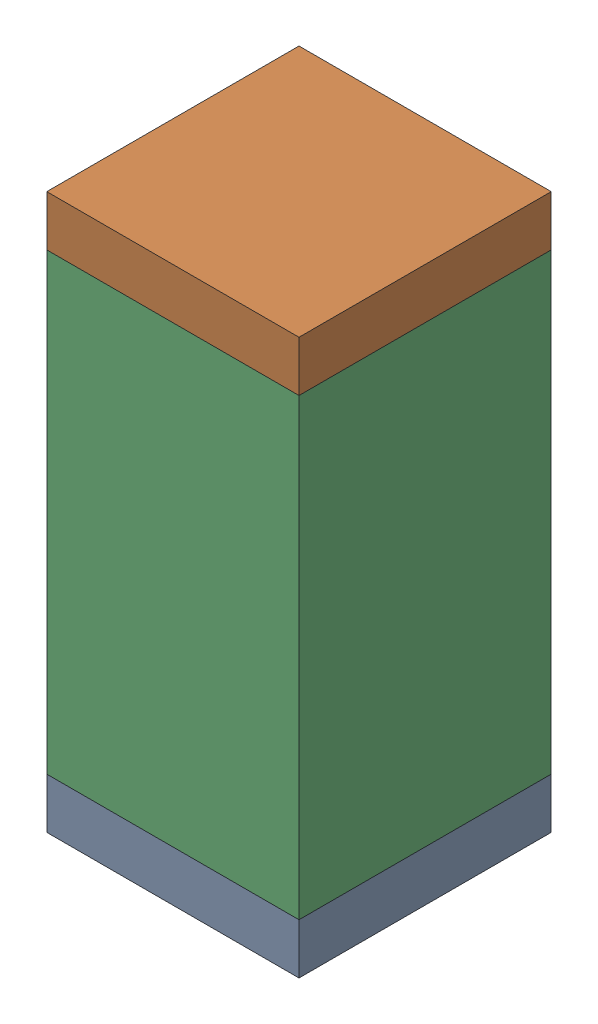
SolidWorks assembly C121, configuration Default. Lengths in mm.
Overall size (0.5 1.1 0.5).
6 component instances, 2 part files, 0 mates.
Components (placement in the parent):
- 810157360-1: 810157360 [Default] at (126.1 18.8 0) size (0.5 0.1 0.5)
  - Extruded_9-1: Extruded_9 [Default] at origin size (0.5 0.1 0.5)
- 810157360-2: 810157360 [Default] at (126.1 19.8 0) size (0.5 0.1 0.5)
  - Extruded_9-1: Extruded_9 [Default] at origin size (0.5 0.1 0.5)
- 791586336-1: 791586336 [Default] at (126.1 19.3 0) size (0.5 0.9 0.5)
  - Extruded_8-1: Extruded_8 [Default] at origin size (0.5 0.9 0.5)
